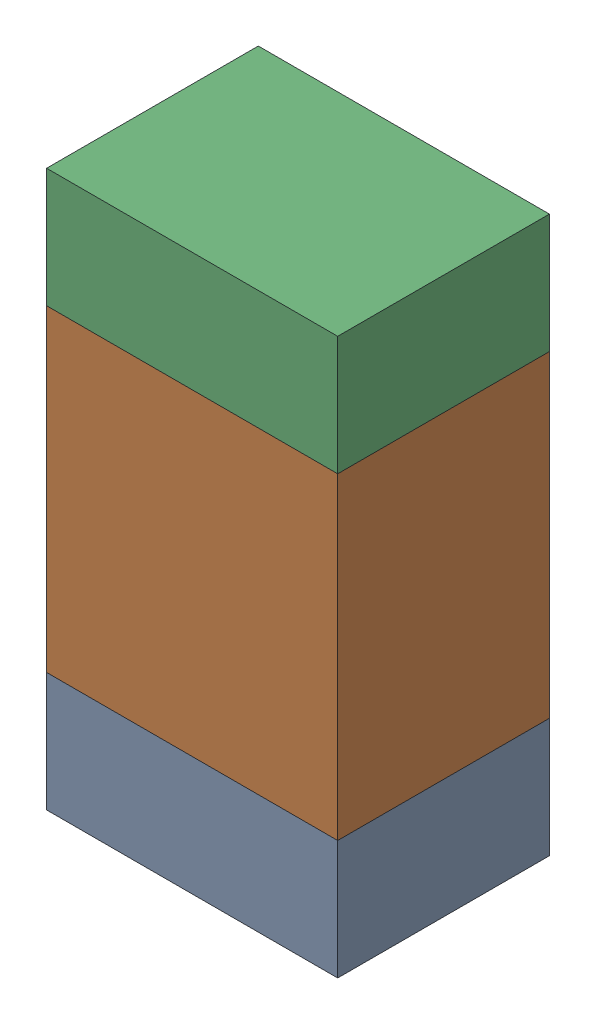
SolidWorks assembly R103_2PCB, configuration Default. Lengths in mm.
Overall size (0.55 1.05 0.4).
6 component instances, 2 part files, 0 mates.
Components (placement in the parent):
- 846483288-1: 846483288 [Default] at (117.5999 93.2876 0) size (0.55 0.22 0.4)
  - Extruded_12-1: Extruded_12 [Default] at origin size (0.55 0.22 0.4)
- 846483424-1: 846483424 [Default] at (117.5999 93.7001 0) size (0.55 0.6 0.4)
  - Extruded_13-1: Extruded_13 [Default] at origin size (0.55 0.6 0.4)
- 846483288-2: 846483288 [Default] at (117.5999 94.1126 0) size (0.55 0.22 0.4)
  - Extruded_12-1: Extruded_12 [Default] at origin size (0.55 0.22 0.4)
